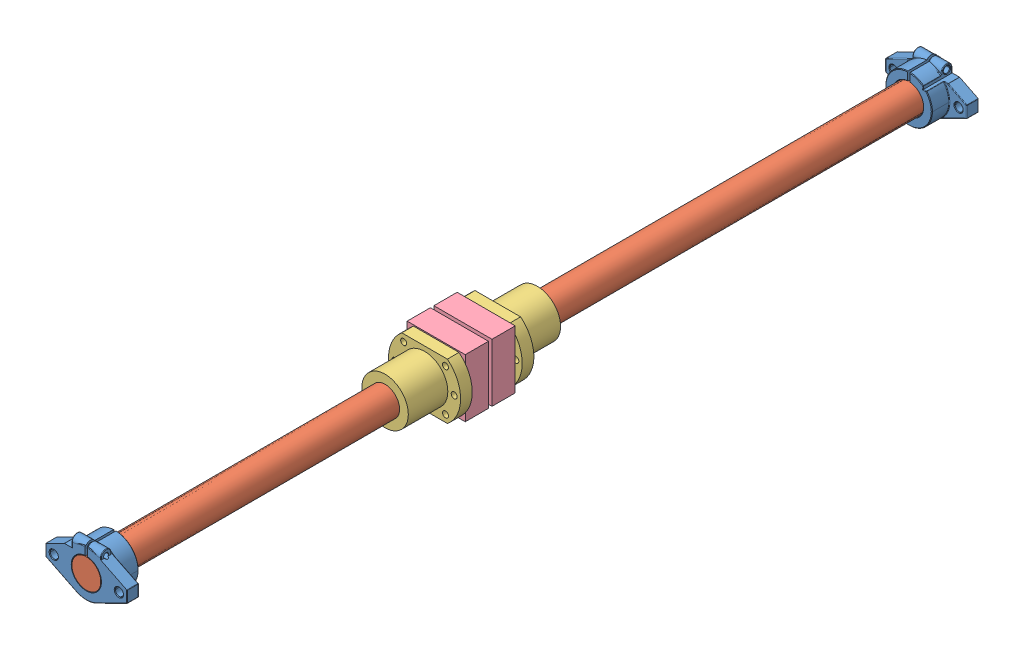
SolidWorks assembly Montagem Guia 2, configuration Default. Lengths in mm.
Overall size (70 50 732.51).
7 component instances, 4 part files, 16 mates.
Components (placement in the parent):
- Shaft support SHF25-1: Shaft support SHF25 [Default] at (4.0374 -3.5446 -12.9006) size (70 42 25.01)
- guia-1: guia [Default] at (4.0374 -3.5446 -12.9006) x (-0.923728 -0.383049 0) z (-0.383049 0.923728 0) size (25 732.5 25)
- Shaft support SHF25-2: Shaft support SHF25 [Default] at (4.0374 -3.5446 719.5994) x (-1 0 0) z (0 0 -1) size (70 42 25.01)
- LMF25UU-1: LMF25UU [Default] at (4.0374 -3.5446 418.5654) x (0 1 0) z (1 0 0) size (48 44 62)
- LMF25UU-2: LMF25UU [Default] at (4.0374 -3.5446 375.5654) x (0 1 0) z (-1 0 0) size (48 44 62)
- bucha-1: bucha [Default] at (4.0374 -3.5446 418.5654) x (1 0 0) z (0 1 0) size (50 20 50)
- bucha-2: bucha [Default] at (4.0374 -3.5446 395.5654) x (1 0 0) z (0 1 0) size (50 20 50)
Mates (geometry in assembly coordinates):
- Coincident1: coincident aligned: plane of Shaft support SHF25-1 through (4.0374 -3.5446 -12.9006) normal (0 0 -1); plane of guia-1 through (4.0374 -3.5446 -12.9006) normal (0 0 -1)
- Concentric1: concentric aligned: cylinder of Shaft support SHF25-1 through (4.0374 -3.5446 12.0994) axis (0 0 -1) radius 12.5; cylinder of guia-1 through (4.0374 -3.5446 719.5994) axis (0 0 -1) radius 12.5
- Concentric2: concentric anti-aligned: cylinder of guia-1 through (4.0374 -3.5446 719.5994) axis (0 0 -1) radius 12.5; cylinder of Shaft support SHF25-2 through (4.0374 -3.5446 694.5994) axis (0 0 1) radius 12.5
- Coincident2: coincident aligned: plane of guia-1 through (4.0374 -3.5446 719.5994) normal (0 0 1); plane of Shaft support SHF25-2 through (4.0374 -3.5446 719.5994) normal (0 0 1)
- Parallel1: parallel aligned: plane of Shaft support SHF25-1 through (-30.9626 -3.5446 -2.9006) normal (-1 0 0); plane of Shaft support SHF25-2 through (-30.9626 -3.5446 709.5994) normal (-1 0 0)
- Concentric3: concentric anti-aligned: cylinder of guia-1 through (4.0374 -3.5446 719.5994) axis (0 0 -1) radius 12.5; cylinder of LMF25UU-1 through (4.0374 -3.5446 418.5644) axis (0 0 1) radius 12.5
- Concentric4: concentric anti-aligned: cylinder of guia-1 through (4.0374 -3.5446 719.5994) axis (0 0 -1) radius 12.5; cylinder of LMF25UU-2 through (4.0374 -3.5446 331.5654) axis (0 0 1) radius 20
- Distance1: distance = 43 mm anti-aligned: plane of LMF25UU-2 through (4.0374 -3.5446 375.5654) normal (0 0 1); plane of LMF25UU-1 through (4.0374 -3.5446 418.5654) normal (0 0 -1)
- Coincident5: coincident aligned: plane of LMF25UU-1 through (-15.584 20.4554 428.5654) normal (0 1 0); plane of LMF25UU-2 through (23.6588 20.4554 365.5654) normal (0 1 0)
- Perpendicular1: perpendicular: plane of Shaft support SHF25-2 through (39.0374 -3.5446 709.5994) normal (1 0 0); plane of LMF25UU-1 through (-15.584 20.4554 428.5654) normal (0 1 0)
- Concentric5: concentric anti-aligned: cylinder of guia-1 through (4.0374 -3.5446 719.5994) axis (0 0 -1) radius 12.5; cylinder of bucha-1 through (4.0374 -3.5446 398.5654) axis (0 0 1) radius 12.5
- Parallel3: parallel aligned: plane of LMF25UU-1 through (-15.584 -27.5446 428.5654) normal (0 -1 0); plane of bucha-1 through (-20.9626 -28.5446 398.5654) normal (0 -1 0)
- Coincident8: coincident anti-aligned: plane of LMF25UU-1 through (4.0374 -3.5446 418.5654) normal (0 0 -1); plane of bucha-1 through (4.0374 -3.5446 418.5654) normal (0 0 1)
- Concentric6: concentric anti-aligned: cylinder of guia-1 through (4.0374 -3.5446 719.5994) axis (0 0 -1) radius 12.5; cylinder of bucha-2 through (4.0374 -3.5446 375.5654) axis (0 0 1) radius 12.5
- Coincident9: coincident anti-aligned: plane of LMF25UU-2 through (4.0374 -3.5446 375.5654) normal (0 0 1); plane of bucha-2 through (4.0374 -3.5446 375.5654) normal (0 0 -1)
- Coincident10: coincident aligned: plane of bucha-1 through (29.0374 21.4554 398.5654) normal (1 0 0); plane of bucha-2 through (29.0374 21.4554 375.5654) normal (1 0 0)
